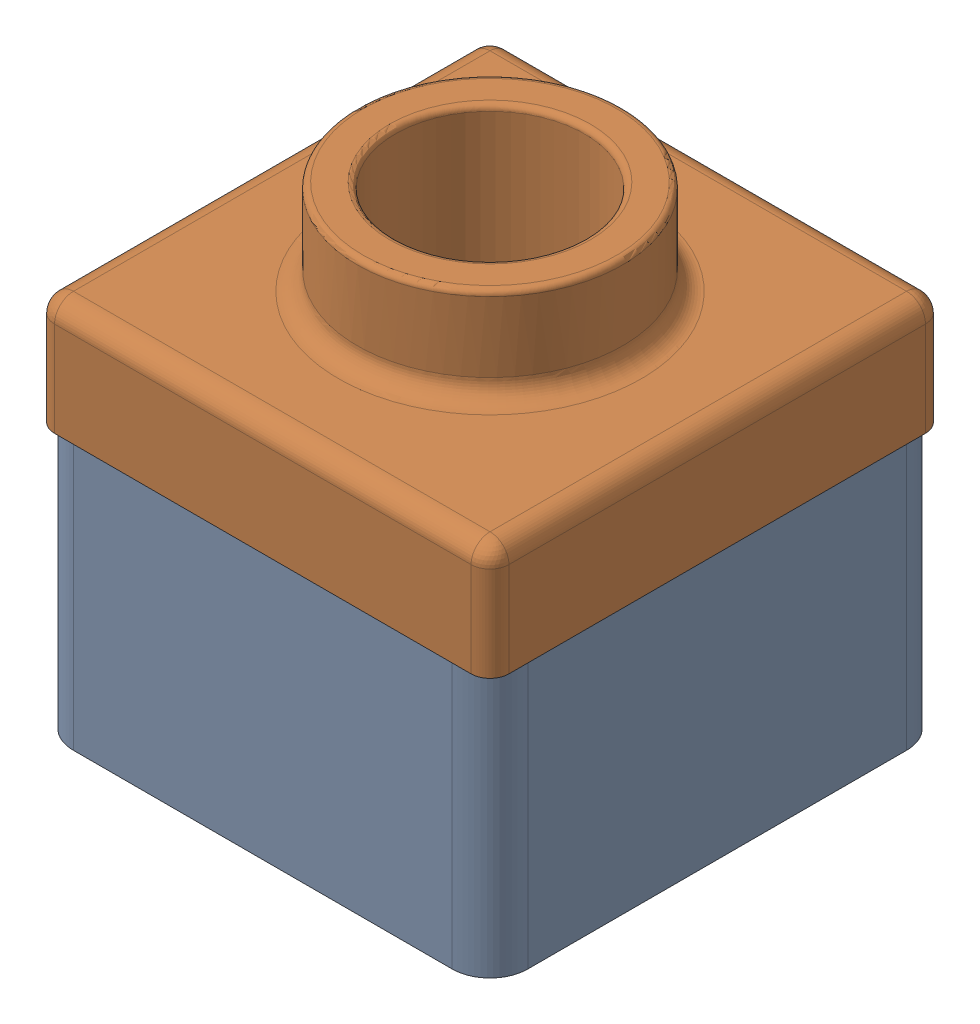
SolidWorks assembly Assem1, configuration Default. Lengths in mm.
Overall size (120 125 120).
2 component instances, 2 part files, 3 mates.
Components (placement in the parent):
- Part2_tutorial-1: Part2_tutorial [Default] at (302.7632 -70 70.7014) size (120 90 120)
- part_tutorial-1: part_tutorial [Default] at (302.7632 0 70.7014) size (120 55 120)
Mates (geometry in assembly coordinates):
- Coincident3: coincident: plane of part_tutorial-1 through (269.3645 0 70.7014) normal (0 -1 0); plane of Part2_tutorial-1 through (352.7632 0 20.7014) normal (0 1 0)
- Coincident5: coincident: plane of Part2_tutorial-1 through (242.7632 20 10.7014) normal (0 0 -1); plane of part_tutorial-1 through (242.7632 30 10.7014) normal (0 0 -1)
- Coincident6: coincident aligned: plane of Part2_tutorial-1 through (242.7632 20 130.7014) normal (-1 0 0); plane of part_tutorial-1 through (242.7632 30 130.7014) normal (-1 0 0)
